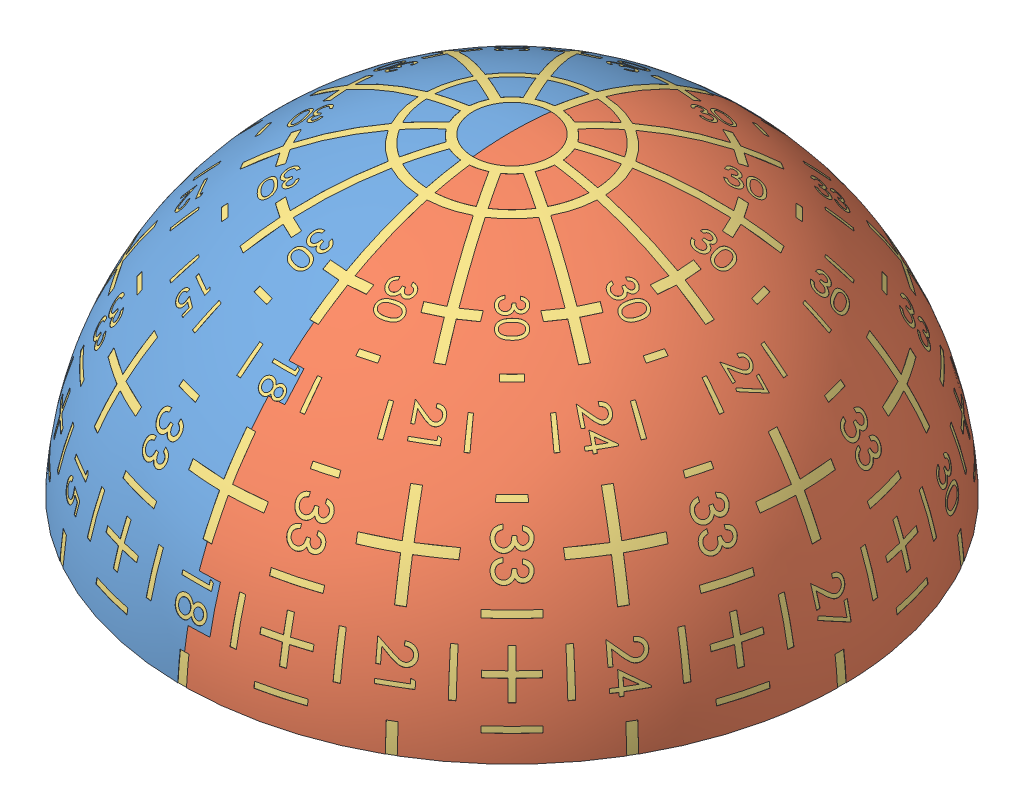
SolidWorks assembly puzzle, configuration Default. Lengths in mm.
Overall size (183.03 89.81 183.03).
3 component instances, 3 part files, 5 mates.
Components (placement in the parent):
- TopWhiteOuter-1: TopWhiteOuter [Default] at (34.8611 45.3576 67.9155) size (47.25 42.35 88.79)
- TopBlackOuter-1: TopBlackOuter [Default] at (34.8611 45.3576 67.9155) size (44.4 42.35 88.79)
- TopPlug-1: TopPlug [Default] at (34.8611 45.4076 67.9155) size (88.71 42.35 88.71)
Mates (geometry in assembly coordinates):
- Coincident1: coincident: circle of TopWhiteOuter-1; circle of TopBlackOuter-1
- Coincident5: coincident: plane of TopWhiteOuter-1 through (34.8611 47.4576 67.9155) normal (0 -1 0); plane of TopBlackOuter-1 through (34.8611 47.4576 67.9155) normal (0 -1 0)
- Concentric3: concentric: circle of TopBlackOuter-1; circle of TopPlug-1
- Coincident13: coincident: plane of TopBlackOuter-1 through (34.8611 47.4576 67.9155) normal (0 -1 0); plane of TopPlug-1 through (93.9891 47.4576 23.5155) normal (0 -1 0)
- Coincident14: coincident: plane of TopWhiteOuter-1 through (34.8611 47.4576 67.9155) normal (0 -1 0); plane of TopPlug-1 through (93.9891 47.4576 23.5155) normal (0 -1 0)
